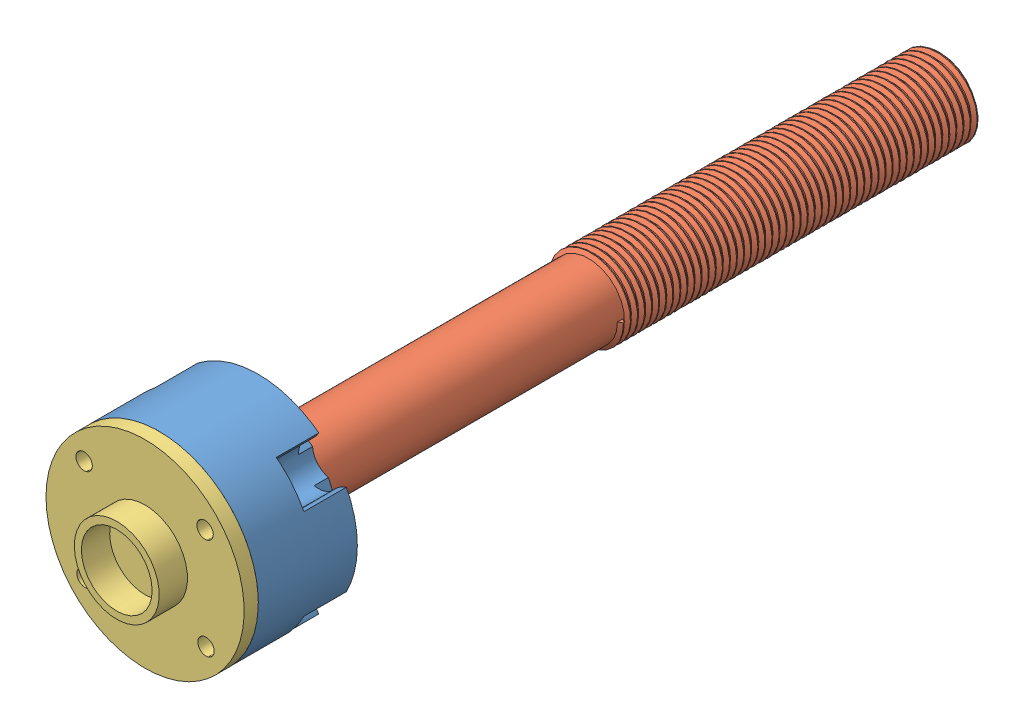
SolidWorks assembly Steering thor joint(RH), configuration Default. Lengths in mm.
Overall size (14.13 14.13 58.56).
3 component instances, 3 part files, 4 mates.
Components (placement in the parent):
- bolt head(RH)-1: bolt head(RH) [Default] at (-18.4031 26.2188 19.7392) size (14 14 8)
- Bogie bolt(RH)-1: Bogie bolt(RH) [Default] at (-18.4064 26.2246 14.7392) x (-1 0 0) z (0 0 -1) size (9 10.39 55.56)
- Bolt servo connector(RH)-1: Bolt servo connector(RH) [Default] at (-18.4031 26.2188 19.7392) x (0.99996 0.008969 0) z (0 0 1) size (14 14 3)
Mates (geometry in assembly coordinates):
- Coincident14: coincident: plane of bolt head(RH)-1 through (-18.4031 26.2188 19.7392) normal (0 0 1); plane of Bogie bolt(RH)-1 through (-18.4064 26.2246 19.7392) normal (0 0 1)
- Coincident16: coincident: line of bolt head(RH)-1 through (-15.0425 29.4786 19.7392) axis (-0.866025 0.5 0); line of Bogie bolt(RH)-1 through (-18.4064 31.4207 19.7392) axis (0.866025 -0.5 0)
- Coincident18: coincident: plane of bolt head(RH)-1 through (-22.9064 26.2188 14.7392) normal (1 0 0); plane of Bogie bolt(RH)-1 through (-22.9064 23.6265 19.7392) normal (-1 0 0)
- Coincident19: coincident: circle of bolt head(RH)-1; circle of Bolt servo connector(RH)-1
